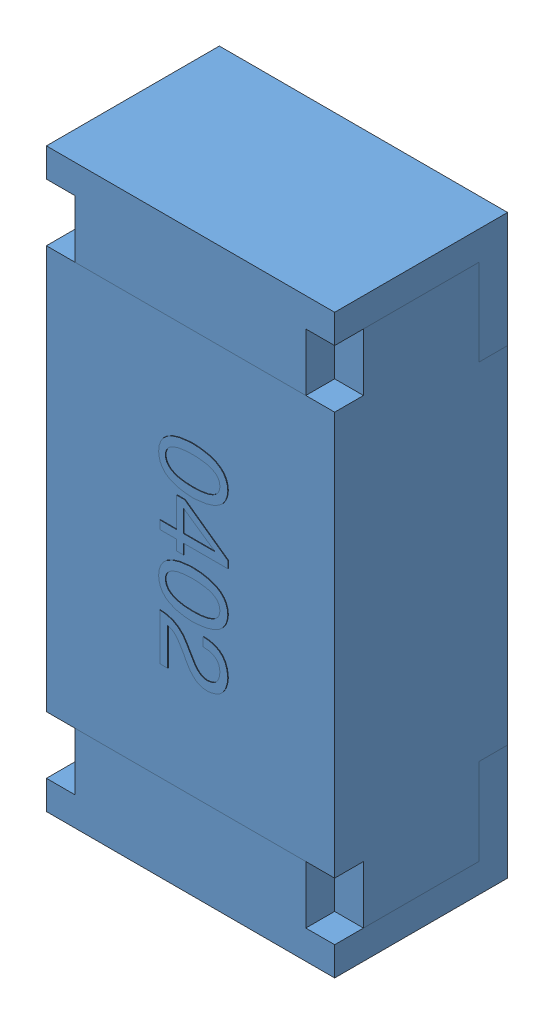
SolidWorks assembly 0402电阻, configuration 默认. Lengths in mm.
Overall size (0.5 1 0.3).
2 component instances, 1 part files, 0 mates.
Components (placement in the parent):
- R_0402^0402电阻-1: R_0402^0402电阻 [默认] at (138.684 119.126 0) x (0 -1 0) z (0 0 1) size (1 0.5 0.3) (virtual)
  - R_0402-23^R_0402_0402电阻-1: R_0402-23^R_0402_0402电阻 [默认] at origin size (1 0.5 0.3) (virtual)
